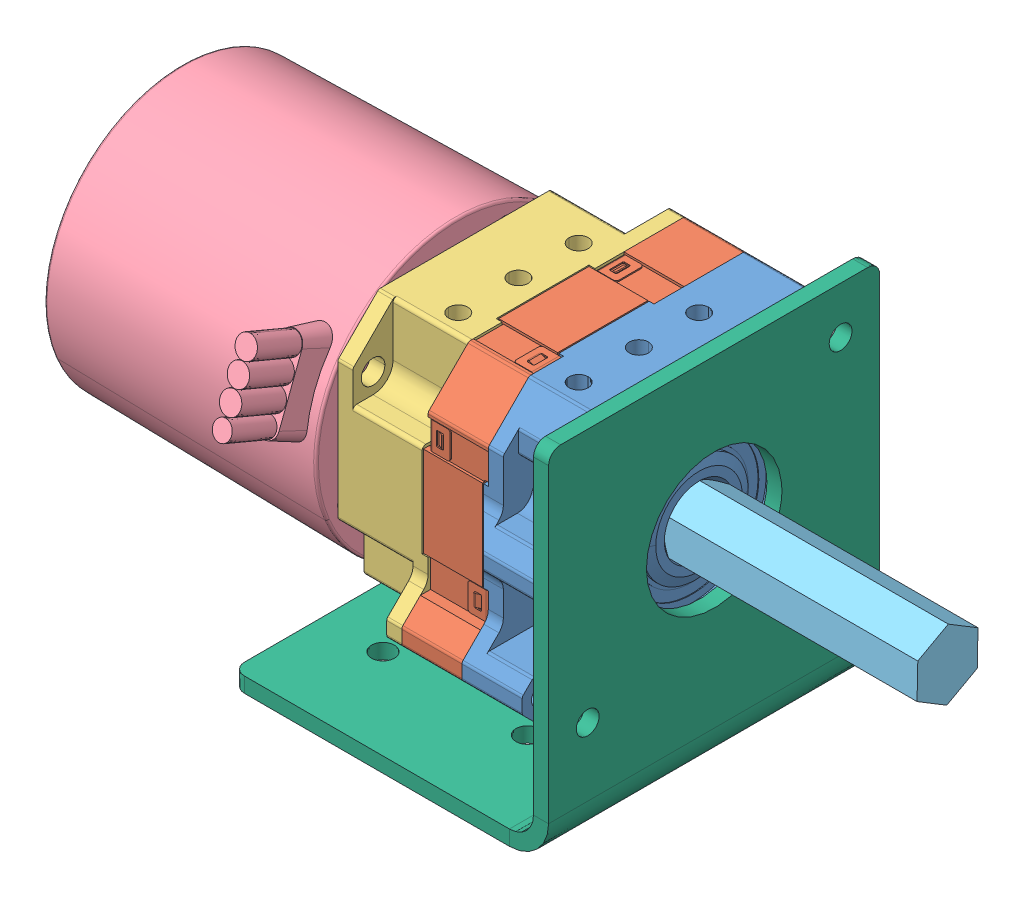
SolidWorks assembly Intake Motor stuff, configuration Default. Lengths in mm.
Overall size (161.54 91.1 89.11).
6 component instances, 6 part files, 12 mates.
Components (placement in the parent):
- REV-21-2104.step-1: REV-21-2104.step [Default] at (21.4566 31.3768 49.041) size (23.2 50.8 61.92)
- REV-21-2101.step-1: REV-21-2101.step [Default] at (5.5816 31.3768 49.0366) x (0 0 -1) z (1 0 0) size (61.91 50.8 16.85)
- REV-21-2106.step-1: REV-21-2106.step [Default] at (-10.2934 31.3768 49.0366) x (0 0 -1) z (1 0 0) size (61.91 50.8 19.05)
- Neo.step-1: Neo.step [Default] at (-19.8184 31.3768 49.0366) x (0 0.386023 -0.922489) z (1 0 0) size (68.13 68.01 93.35)
- 2.5in Axle-1: 2.5in Axle [Default] at (19.8691 31.3803 49.0346) x (0 -0.742573 0.669766) z (1 0 0) size (13.85 14.4 63.5)
- Bracket for neo-2: Bracket for neo [Default] at (30.9816 25.0268 49.041) size (66.67 76.2 69.85)
Mates (geometry in assembly coordinates):
- Coincident1: coincident anti-aligned: plane of REV-21-2104.step-1 through (11.9316 31.3768 49.041) normal (-1 0 0); plane of REV-21-2101.step-1 through (11.9316 31.3768 49.0366) normal (1 0 0)
- Concentric1: concentric anti-aligned: circle of REV-21-2104.step-1; circle of REV-21-2101.step-1
- Coincident2: coincident anti-aligned: plane of REV-21-2101.step-1 through (-0.7684 31.3768 49.0366) normal (-1 0 0); plane of REV-21-2106.step-1 through (-0.7684 31.3768 49.0366) normal (1 0 0)
- Coincident4: coincident: cylinder of REV-21-2101.step-1 through (11.9316 52.8081 22.0491) axis (1 0 0) radius 2.5; circle of REV-21-2106.step-1
- Concentric2: concentric anti-aligned: circle of REV-21-2106.step-1; circle of Neo.step-1
- Coincident5: coincident anti-aligned: plane of REV-21-2106.step-1 through (-19.8184 31.3768 49.0366) normal (-1 0 0); plane of Neo.step-1 through (-19.8184 31.3768 49.0366) normal (1 0 0)
- Concentric3: concentric anti-aligned: cylinder of REV-21-2101.step-1 through (11.9316 9.9456 76.0241) axis (1 0 0) radius 2.5; cylinder of REV-21-2106.step-1 through (-0.7684 9.9456 76.0241) axis (-1 0 0) radius 2.5
- Coincident11: coincident: plane of REV-21-2104.step-1 through (19.8691 27.5698 42.7659) normal (0 0.021721 0.999764); plane of 2.5in Axle-1 through (83.3691 27.5771 42.7657) normal (0 -0.021721 -0.999764)
- Coincident12: coincident: plane of REV-21-2104.step-1 through (19.8691 34.9077 42.6065) normal (0 -0.85496 0.518693); plane of 2.5in Axle-1 through (83.3691 34.9077 42.6065) normal (0 0.85496 -0.518693)
- Coincident13: coincident: plane of REV-21-2104.step-1 through (19.8691 31.3768 49.041) normal (1 0 0); plane of 2.5in Axle-1 through (19.8691 31.3803 49.0346) normal (-1 0 0)
- Concentric5: concentric: circle of REV-21-2104.step-1; cylinder of Bracket for neo-2 through (30.9816 31.3768 49.041) axis (-1 0 0) radius 14.2875
- Coincident14: coincident anti-aligned: plane of REV-21-2104.step-1 through (30.9816 31.3768 49.041) normal (1 0 0); plane of Bracket for neo-2 through (30.9816 25.0268 49.041) normal (-1 0 0)
